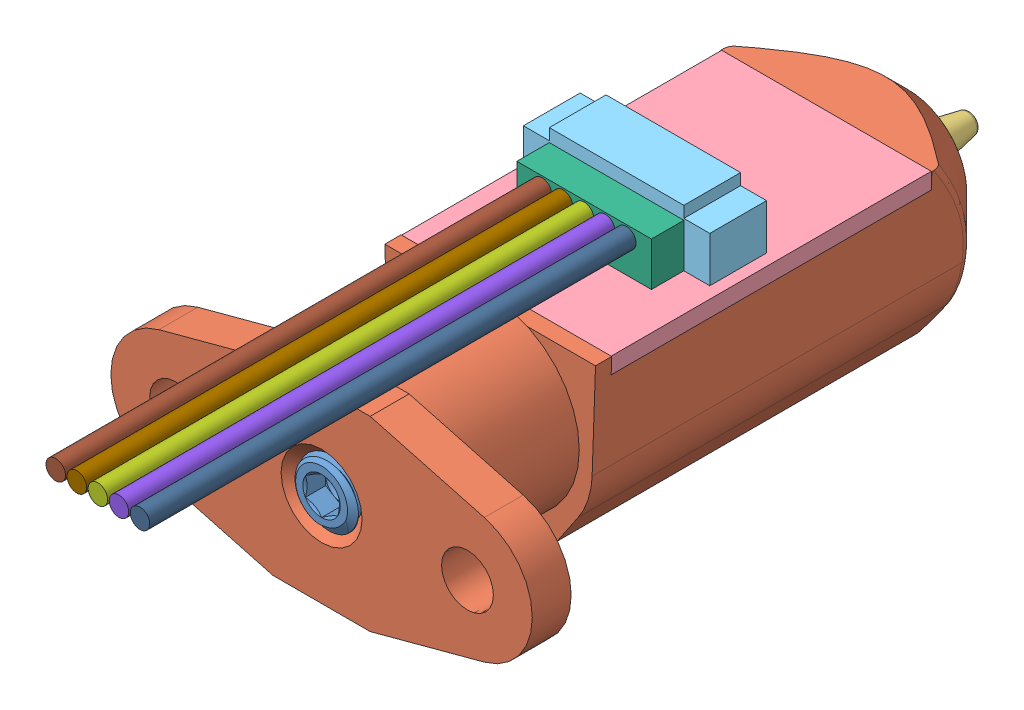
SolidWorks assembly BLTouch-Smart V3.1, configuration BLTouch-Smart V3.1. Lengths in mm.
Overall size (26 15.35 53.8).
11 component instances, 11 part files, 0 mates.
Components (placement in the parent):
- 93245A111-1: 93245A111 [93245A111] at (0 0 -2.4994) size (4.89 4.75 5.01)
- BL-touch-1: BL-touch [BL-touch] at origin size (26 12.6 36.68)
- BL-touch-0-1: BL-touch-0 [BL-touch-0] at origin size (2.08 2.08 10)
- BL-touch-1-1: BL-touch-1 [BL-touch-1] at origin size (12.93 1 19.75)
- BL-touch-2-1: BL-touch-2 [BL-touch-2] at origin size (11.5 3.5 3.5)
- BL-touch-3-1: BL-touch-3 [BL-touch-3] at origin size (8.3 2.7 2)
- BL-touch-4-1: BL-touch-4 [BL-touch-4] at origin size (1.2 1.2 30)
- BL-touch-5-1: BL-touch-5 [BL-touch-5] at origin size (1.2 1.2 30)
- BL-touch-6-1: BL-touch-6 [BL-touch-6] at origin size (1.2 1.2 30)
- BL-touch-7-1: BL-touch-7 [BL-touch-7] at origin size (1.2 1.2 30)
- BL-touch-8-1: BL-touch-8 [BL-touch-8] at origin size (1.2 1.2 30)
